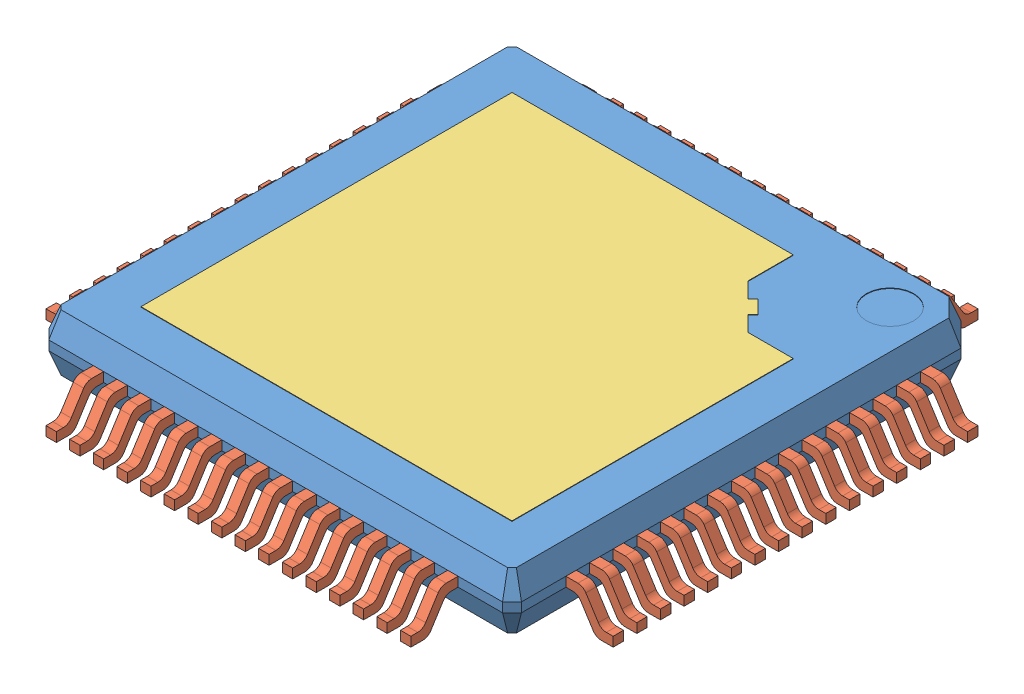
SolidWorks assembly Assem1, configuration Default. Lengths in mm.
Overall size (12 1.31 12).
66 component instances, 3 part files, 12 mates.
Components (placement in the parent):
- Body-1: Body [Default] at (0 0.7 0) size (10 1.2 10)
- Pin-1: Pin [Default] at (-5 0.7 -3.75) x (-1 0 0) z (0 1 0) size (1 0.22 0.8)
- Pin-2: Pin [Default] at (3.75 0.7 -5) x (0 0 -1) z (0 1 0) size (1 0.22 0.8)
- Pin-3: Pin [Default] at (-5 0.7 -3.25) x (-1 0 0) z (0 1 0) size (1 0.22 0.8)
- Pin-4: Pin [Default] at (-5 0.7 -2.75) x (-1 0 0) z (0 1 0) size (1 0.22 0.8)
- Pin-5: Pin [Default] at (-5 0.7 -2.25) x (-1 0 0) z (0 1 0) size (1 0.22 0.8)
- Pin-6: Pin [Default] at (-5 0.7 -1.75) x (-1 0 0) z (0 1 0) size (1 0.22 0.8)
- Pin-7: Pin [Default] at (-5 0.7 -1.25) x (-1 0 0) z (0 1 0) size (1 0.22 0.8)
- Pin-8: Pin [Default] at (-5 0.7 -0.75) x (-1 0 0) z (0 1 0) size (1 0.22 0.8)
- Pin-9: Pin [Default] at (-5 0.7 -0.25) x (-1 0 0) z (0 1 0) size (1 0.22 0.8)
- Pin-10: Pin [Default] at (-5 0.7 0.25) x (-1 0 0) z (0 1 0) size (1 0.22 0.8)
- Pin-11: Pin [Default] at (-5 0.7 0.75) x (-1 0 0) z (0 1 0) size (1 0.22 0.8)
- Pin-12: Pin [Default] at (-5 0.7 1.25) x (-1 0 0) z (0 1 0) size (1 0.22 0.8)
- Pin-13: Pin [Default] at (-5 0.7 1.75) x (-1 0 0) z (0 1 0) size (1 0.22 0.8)
- Pin-14: Pin [Default] at (-5 0.7 2.25) x (-1 0 0) z (0 1 0) size (1 0.22 0.8)
- Pin-15: Pin [Default] at (-5 0.7 2.75) x (-1 0 0) z (0 1 0) size (1 0.22 0.8)
- Pin-16: Pin [Default] at (-5 0.7 3.25) x (-1 0 0) z (0 1 0) size (1 0.22 0.8)
- Pin-17: Pin [Default] at (-5 0.7 3.75) x (-1 0 0) z (0 1 0) size (1 0.22 0.8)
- Pin-18: Pin [Default] at (5 0.7 -3.75) x (1 0 0) z (0 1 0) size (1 0.22 0.8)
- Pin-19: Pin [Default] at (5 0.7 -3.25) x (1 0 0) z (0 1 0) size (1 0.22 0.8)
- Pin-20: Pin [Default] at (5 0.7 -2.75) x (1 0 0) z (0 1 0) size (1 0.22 0.8)
- Pin-21: Pin [Default] at (5 0.7 -2.25) x (1 0 0) z (0 1 0) size (1 0.22 0.8)
- Pin-22: Pin [Default] at (5 0.7 -1.75) x (1 0 0) z (0 1 0) size (1 0.22 0.8)
- Pin-23: Pin [Default] at (5 0.7 -1.25) x (1 0 0) z (0 1 0) size (1 0.22 0.8)
- Pin-24: Pin [Default] at (5 0.7 -0.75) x (1 0 0) z (0 1 0) size (1 0.22 0.8)
- Pin-25: Pin [Default] at (5 0.7 -0.25) x (1 0 0) z (0 1 0) size (1 0.22 0.8)
- Pin-26: Pin [Default] at (5 0.7 0.25) x (1 0 0) z (0 1 0) size (1 0.22 0.8)
- Pin-27: Pin [Default] at (5 0.7 0.75) x (1 0 0) z (0 1 0) size (1 0.22 0.8)
- Pin-28: Pin [Default] at (5 0.7 1.25) x (1 0 0) z (0 1 0) size (1 0.22 0.8)
- Pin-29: Pin [Default] at (5 0.7 1.75) x (1 0 0) z (0 1 0) size (1 0.22 0.8)
- Pin-30: Pin [Default] at (5 0.7 2.25) x (1 0 0) z (0 1 0) size (1 0.22 0.8)
- Pin-31: Pin [Default] at (5 0.7 2.75) x (1 0 0) z (0 1 0) size (1 0.22 0.8)
- Pin-32: Pin [Default] at (5 0.7 3.25) x (1 0 0) z (0 1 0) size (1 0.22 0.8)
- Pin-33: Pin [Default] at (5 0.7 3.75) x (1 0 0) z (0 1 0) size (1 0.22 0.8)
- Pin-34: Pin [Default] at (3.25 0.7 -5) x (0 0 -1) z (0 1 0) size (1 0.22 0.8)
- Pin-35: Pin [Default] at (2.75 0.7 -5) x (0 0 -1) z (0 1 0) size (1 0.22 0.8)
- Pin-36: Pin [Default] at (2.25 0.7 -5) x (0 0 -1) z (0 1 0) size (1 0.22 0.8)
- Pin-37: Pin [Default] at (1.75 0.7 -5) x (0 0 -1) z (0 1 0) size (1 0.22 0.8)
- Pin-38: Pin [Default] at (1.25 0.7 -5) x (0 0 -1) z (0 1 0) size (1 0.22 0.8)
- Pin-39: Pin [Default] at (0.75 0.7 -5) x (0 0 -1) z (0 1 0) size (1 0.22 0.8)
- Pin-40: Pin [Default] at (0.25 0.7 -5) x (0 0 -1) z (0 1 0) size (1 0.22 0.8)
- Pin-41: Pin [Default] at (-0.25 0.7 -5) x (0 0 -1) z (0 1 0) size (1 0.22 0.8)
- Pin-42: Pin [Default] at (-0.75 0.7 -5) x (0 0 -1) z (0 1 0) size (1 0.22 0.8)
- Pin-43: Pin [Default] at (-1.25 0.7 -5) x (0 0 -1) z (0 1 0) size (1 0.22 0.8)
- Pin-44: Pin [Default] at (-1.75 0.7 -5) x (0 0 -1) z (0 1 0) size (1 0.22 0.8)
- Pin-45: Pin [Default] at (-2.25 0.7 -5) x (0 0 -1) z (0 1 0) size (1 0.22 0.8)
- Pin-46: Pin [Default] at (-2.75 0.7 -5) x (0 0 -1) z (0 1 0) size (1 0.22 0.8)
- Pin-47: Pin [Default] at (-3.25 0.7 -5) x (0 0 -1) z (0 1 0) size (1 0.22 0.8)
- Pin-48: Pin [Default] at (-3.75 0.7 -5) x (0 0 -1) z (0 1 0) size (1 0.22 0.8)
- Pin-49: Pin [Default] at (3.75 0.7 5) x (0 0 1) z (0 1 0) size (1 0.22 0.8)
- Pin-50: Pin [Default] at (3.25 0.7 5) x (0 0 1) z (0 1 0) size (1 0.22 0.8)
- Pin-51: Pin [Default] at (2.75 0.7 5) x (0 0 1) z (0 1 0) size (1 0.22 0.8)
- Pin-52: Pin [Default] at (2.25 0.7 5) x (0 0 1) z (0 1 0) size (1 0.22 0.8)
- Pin-53: Pin [Default] at (1.75 0.7 5) x (0 0 1) z (0 1 0) size (1 0.22 0.8)
- Pin-54: Pin [Default] at (1.25 0.7 5) x (0 0 1) z (0 1 0) size (1 0.22 0.8)
- Pin-55: Pin [Default] at (0.75 0.7 5) x (0 0 1) z (0 1 0) size (1 0.22 0.8)
- Pin-56: Pin [Default] at (0.25 0.7 5) x (0 0 1) z (0 1 0) size (1 0.22 0.8)
- Pin-57: Pin [Default] at (-0.25 0.7 5) x (0 0 1) z (0 1 0) size (1 0.22 0.8)
- Pin-58: Pin [Default] at (-0.75 0.7 5) x (0 0 1) z (0 1 0) size (1 0.22 0.8)
- Pin-59: Pin [Default] at (-1.25 0.7 5) x (0 0 1) z (0 1 0) size (1 0.22 0.8)
- Pin-60: Pin [Default] at (-1.75 0.7 5) x (0 0 1) z (0 1 0) size (1 0.22 0.8)
- Pin-61: Pin [Default] at (-2.25 0.7 5) x (0 0 1) z (0 1 0) size (1 0.22 0.8)
- Pin-62: Pin [Default] at (-2.75 0.7 5) x (0 0 1) z (0 1 0) size (1 0.22 0.8)
- Pin-63: Pin [Default] at (-3.25 0.7 5) x (0 0 1) z (0 1 0) size (1 0.22 0.8)
- Pin-64: Pin [Default] at (-3.75 0.7 5) x (0 0 1) z (0 1 0) size (1 0.22 0.8)
- EP-1: EP [Default] at (0 1.11 0) x (0 0 1) z (-1 0 0) size (7.85 0.2 7.85)
Mates (geometry in assembly coordinates):
- Coincident1: coincident aligned: plane of Body-1 through (0 0.7 0) normal (1 0 0)
- Coincident2: coincident aligned: plane of Body-1 through (0 0.7 0) normal (0 0 1)
- Distance1: distance = 0.7 mm: plane of assembly through (0 0 0) normal (0 1 0); plane of assembly; plane of Body-1 through (0 0.7 0) normal (0 1 0)
- Coincident4: coincident anti-aligned: plane of Body-1 through (-5 0.8 5) normal (-1 0 0); plane of Pin-1 through (-5 0.8 -3.64) normal (1 0 0)
- Coincident5: coincident aligned: plane of Body-1 through (0 0.7 0) normal (0 1 0); plane of Pin-1 through (-5 0.7 -3.75) normal (0 1 0)
- Distance2: distance = 3.75 mm: plane of assembly through (0 0 0) normal (0 0 1); plane of assembly; plane of Pin-1 through (-5 0.7 -3.75) normal (0 0 1)
- Coincident7: coincident anti-aligned: plane of Body-1 through (-5 0.8 -5) normal (0 0 -1); plane of Pin-2 through (3.64 0.8 -5) normal (0 0 1)
- Coincident8: coincident aligned: plane of Body-1 through (0 0.7 0) normal (0 1 0); plane of Pin-2 through (3.75 0.7 -5) normal (0 1 0)
- Distance3: distance = 3.75 mm anti-aligned: plane of Pin-2 through (3.75 0.7 -5) normal (-1 0 0)
- Coincident10: coincident aligned: plane of EP-1 through (0 1.11 0) normal (0 0 1)
- Coincident11: coincident anti-aligned: plane of EP-1 through (0 1.11 0) normal (-1 0 0)
- Distance4: distance = 0.01 mm aligned: plane of EP-1 through (0 1.31 0) normal (0 1 0); plane of Body-1 through (0 1.3 0) normal (0 1 0)
